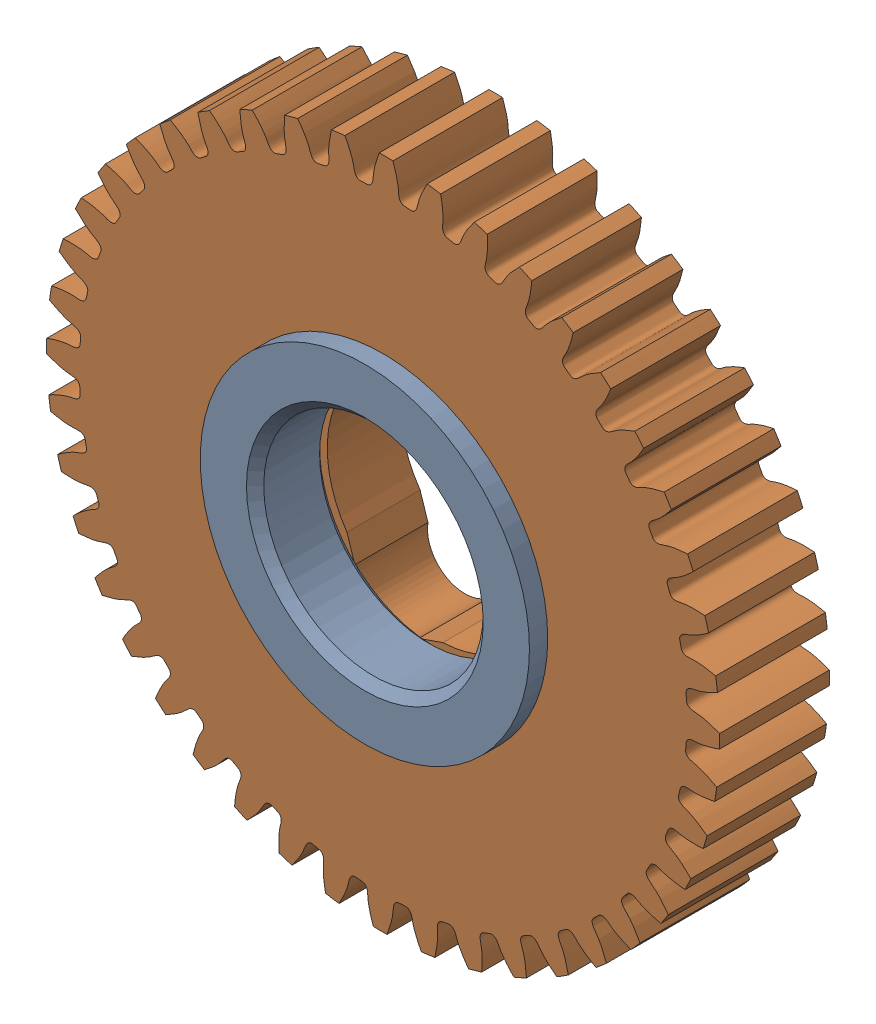
SolidWorks assembly Mirror217-2709-101 Rev1, configuration Default. Lengths in mm.
Overall size (62.31 62.31 12.7).
2 component instances, 2 part files, 0 mates.
Components (placement in the parent):
- Mirror217-2428-022 Rev1-1: Mirror217-2428-022 Rev1 [Default] at origin size (28.57 28.57 6.1)
- Mirror217-2709-001_44t Steel-1: Mirror217-2709-001_44t Steel [Default] at (0 0 -3.302) x (0.062728 -0.998031 0) z (0 0 1) size (58.74 58.74 11.11)
